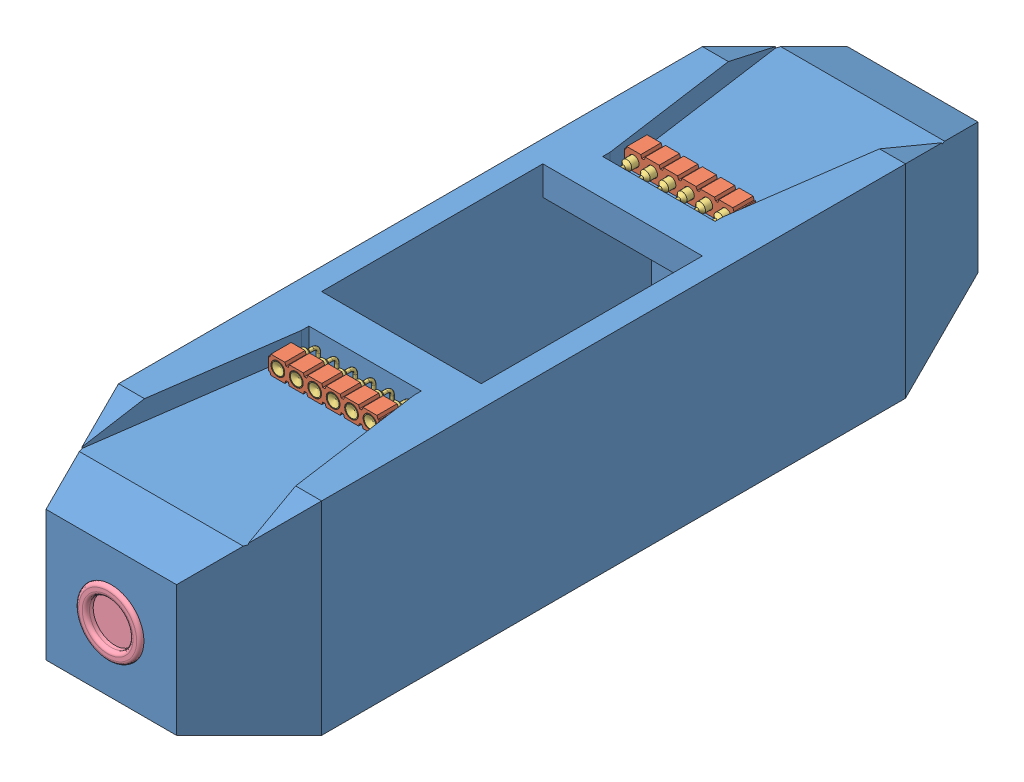
SolidWorks assembly Module_Laser, configuration Default. Lengths in mm.
Overall size (28 28 111.5).
19 component instances, 4 part files, 18 mates.
Components (placement in the parent):
- Module - RB_Gears-1: Module - RB_Gears [Laser] at (37.8746 66.7149 80.4494) size (28 28 110.5)
- mill-max-399-10-106-10-007000-1: mill-max-399-10-106-10-007000 [Default] at (87.4391 79.2849 107.5811) x (1 0 0) z (0 -1 0) size (15.24 5.81 5.74)
  - mill-max-399-10-106-10-007000_P3XX-11-010-00-000000(P306-11-010-00-000000)-1: mill-max-399-10-106-10-007000_P3XX-11-010-00-000000(P306-11-010-00-000000) [Default] at (-56.7488 -1.0694 1.27) size (15.24 2.79 2.54)
  - mill-max-399-10-106-10-007000_1960(1960-0-00-15-00-00-03-0)-1: mill-max-399-10-106-10-007000_1960(1960-0-00-15-00-00-03-0) [Default] at (-50.7044 -1.0694 0) x (0 -1 0) z (1 0 0) size (5.81 5.38 1.83)
  - mill-max-399-10-106-10-007000_1960(1960-0-00-15-00-00-03-0)-2: mill-max-399-10-106-10-007000_1960(1960-0-00-15-00-00-03-0) [Default] at (-43.0844 -1.0694 0) x (0 -1 0) z (1 0 0) size (5.81 5.38 1.83)
  - mill-max-399-10-106-10-007000_1960(1960-0-00-15-00-00-03-0)-3: mill-max-399-10-106-10-007000_1960(1960-0-00-15-00-00-03-0) [Default] at (-55.7844 -1.0694 0) x (0 -1 0) z (1 0 0) size (5.81 5.38 1.83)
  - mill-max-399-10-106-10-007000_1960(1960-0-00-15-00-00-03-0)-4: mill-max-399-10-106-10-007000_1960(1960-0-00-15-00-00-03-0) [Default] at (-48.1644 -1.0694 0) x (0 -1 0) z (1 0 0) size (5.81 5.38 1.83)
  - mill-max-399-10-106-10-007000_1960(1960-0-00-15-00-00-03-0)-5: mill-max-399-10-106-10-007000_1960(1960-0-00-15-00-00-03-0) [Default] at (-53.2444 -1.0694 0) x (0 -1 0) z (1 0 0) size (5.81 5.38 1.83)
  - mill-max-399-10-106-10-007000_1960(1960-0-00-15-00-00-03-0)-6: mill-max-399-10-106-10-007000_1960(1960-0-00-15-00-00-03-0) [Default] at (-45.6244 -1.0694 0) x (0 -1 0) z (1 0 0) size (5.81 5.38 1.83)
- mill-max-399-10-106-10-007000-2: mill-max-399-10-106-10-007000 [Default] at (-11.6898 79.2849 53.3178) x (-1 0 0) z (0 -1 0) size (15.24 5.81 5.74)
  - mill-max-399-10-106-10-007000_P3XX-11-010-00-000000(P306-11-010-00-000000)-1: mill-max-399-10-106-10-007000_P3XX-11-010-00-000000(P306-11-010-00-000000) [Default] at (-56.7488 -1.0694 1.27) size (15.24 2.79 2.54)
  - mill-max-399-10-106-10-007000_1960(1960-0-00-15-00-00-03-0)-1: mill-max-399-10-106-10-007000_1960(1960-0-00-15-00-00-03-0) [Default] at (-50.7044 -1.0694 0) x (0 -1 0) z (1 0 0) size (5.81 5.38 1.83)
  - mill-max-399-10-106-10-007000_1960(1960-0-00-15-00-00-03-0)-2: mill-max-399-10-106-10-007000_1960(1960-0-00-15-00-00-03-0) [Default] at (-43.0844 -1.0694 0) x (0 -1 0) z (1 0 0) size (5.81 5.38 1.83)
  - mill-max-399-10-106-10-007000_1960(1960-0-00-15-00-00-03-0)-3: mill-max-399-10-106-10-007000_1960(1960-0-00-15-00-00-03-0) [Default] at (-55.7844 -1.0694 0) x (0 -1 0) z (1 0 0) size (5.81 5.38 1.83)
  - mill-max-399-10-106-10-007000_1960(1960-0-00-15-00-00-03-0)-4: mill-max-399-10-106-10-007000_1960(1960-0-00-15-00-00-03-0) [Default] at (-48.1644 -1.0694 0) x (0 -1 0) z (1 0 0) size (5.81 5.38 1.83)
  - mill-max-399-10-106-10-007000_1960(1960-0-00-15-00-00-03-0)-5: mill-max-399-10-106-10-007000_1960(1960-0-00-15-00-00-03-0) [Default] at (-53.2444 -1.0694 0) x (0 -1 0) z (1 0 0) size (5.81 5.38 1.83)
  - mill-max-399-10-106-10-007000_1960(1960-0-00-15-00-00-03-0)-6: mill-max-399-10-106-10-007000_1960(1960-0-00-15-00-00-03-0) [Default] at (-45.6244 -1.0694 0) x (0 -1 0) z (1 0 0) size (5.81 5.38 1.83)
- 9mmx24mmLaser-1: 9mmx24mmLaser [Default] at (37.8746 66.7149 112.1994) x (0 0 1) z (-1 0 0) size (24 9 9)
- 9mmx24mmLaser-2: 9mmx24mmLaser [Default] at (37.8746 66.7149 48.6994) x (0 0 -1) z (0.449591 -0.893234 0) size (24 9 9)
Mates (geometry in assembly coordinates):
- Coincident1: coincident anti-aligned: plane of Module - RB_Gears-1 through (37.8746 66.7149 26.6994) normal (0 0 1); plane of ? through (43.8746 71.7149 26.6994) normal (0 0 -1)
- Coincident2: coincident anti-aligned: plane of Module - RB_Gears-1 through (37.8746 66.7149 134.1994) normal (0 0 -1); plane of ? through (31.8746 71.7149 134.1994) normal (0 0 1)
- Concentric1: concentric anti-aligned: cylinder of Module - RB_Gears-1 through (37.8746 66.7149 20.9568) axis (0 0 1) radius 1.5; cylinder of ? through (37.8746 66.7149 22.1994) axis (0 0 -1) radius 1.5
- Concentric2: concentric aligned: cylinder of Module - RB_Gears-1 through (42.3746 66.7149 20.9568) axis (0 0 1) radius 0.95; cylinder of ? through (42.3746 66.7149 27.0994) axis (0 0 1) radius 0.8
- Concentric3: concentric anti-aligned: cylinder of Module - RB_Gears-1 through (37.8746 66.7149 139.9421) axis (0 0 -1) radius 1.5; cylinder of ? through (37.8746 66.7149 138.6994) axis (0 0 1) radius 1.5
- Concentric4: concentric aligned: cylinder of Module - RB_Gears-1 through (42.3746 66.7149 139.9421) axis (0 0 -1) radius 0.95; cylinder of ? through (42.3746 66.7149 133.7994) axis (0 0 -1) radius 0.8
- Tangent1: tangent anti-aligned: plane of Module - RB_Gears-1 through (45.6246 78.0149 100.6994) normal (0 0 1); cylinder of mill-max-399-10-106-10-007000-1/mill-max-399-10-106-10-007000_1960(1960-0-00-15-00-00-03-0)-2 through (44.3546 84.5216 100.928) axis (0 1 0) radius 0.2286
- Tangent2: tangent anti-aligned: plane of Module - RB_Gears-1 through (45.6246 78.0149 100.6994) normal (0 0 1); cylinder of mill-max-399-10-106-10-007000-1/mill-max-399-10-106-10-007000_1960(1960-0-00-15-00-00-03-0)-3 through (31.6546 84.5216 100.928) axis (0 1 0) radius 0.2286
- Tangent3: tangent anti-aligned: plane of Module - RB_Gears-1 through (45.6246 78.0149 60.1994) normal (0 0 -1); cylinder of mill-max-399-10-106-10-007000-2/mill-max-399-10-106-10-007000_1960(1960-0-00-15-00-00-03-0)-2 through (31.3946 84.5216 59.9708) axis (0 1 0) radius 0.2286
- Tangent4: tangent anti-aligned: plane of Module - RB_Gears-1 through (45.6246 78.0149 60.1994) normal (0 0 -1); cylinder of mill-max-399-10-106-10-007000-2/mill-max-399-10-106-10-007000_1960(1960-0-00-15-00-00-03-0)-3 through (44.0946 84.5216 59.9708) axis (0 1 0) radius 0.2286
- Coincident3: coincident anti-aligned: plane of Module - RB_Gears-1 through (37.8746 78.0149 80.4494) normal (0 1 0); plane of mill-max-399-10-106-10-007000-2/mill-max-399-10-106-10-007000_P3XX-11-010-00-000000(P306-11-010-00-000000)-1 through (45.059 78.0149 57.1811) normal (0 -1 0)
- Coincident4: coincident anti-aligned: plane of Module - RB_Gears-1 through (37.8746 78.0149 80.4494) normal (0 1 0); plane of mill-max-399-10-106-10-007000-1/mill-max-399-10-106-10-007000_P3XX-11-010-00-000000(P306-11-010-00-000000)-1 through (30.6903 78.0149 103.7177) normal (0 -1 0)
- Coincident5: coincident anti-aligned: plane of Module - RB_Gears-1 through (45.6246 78.0149 120.6994) normal (-1 0 0); plane of mill-max-399-10-106-10-007000-1/mill-max-399-10-106-10-007000_P3XX-11-010-00-000000(P306-11-010-00-000000)-1 through (45.6246 80.1549 103.7177) normal (1 0 0)
- Coincident7: coincident anti-aligned: plane of Module - RB_Gears-1 through (30.1246 78.0149 40.1994) normal (1 0 0); plane of mill-max-399-10-106-10-007000-2/mill-max-399-10-106-10-007000_P3XX-11-010-00-000000(P306-11-010-00-000000)-1 through (30.1246 80.1549 57.1811) normal (-1 0 0)
- Concentric5: concentric anti-aligned: cylinder of Module - RB_Gears-1 through (37.8746 66.7149 93.1774) axis (0 0 -1) radius 4.5; cylinder of 9mmx24mmLaser-2 through (37.8746 66.7149 24.6994) axis (0 0 1) radius 4.5
- Concentric6: concentric anti-aligned: cylinder of Module - RB_Gears-1 through (37.8746 66.7149 67.7215) axis (0 0 1) radius 4.5; cylinder of 9mmx24mmLaser-1 through (37.8746 66.7149 136.1994) axis (0 0 -1) radius 4.5
- Coincident8: coincident anti-aligned: plane of Module - RB_Gears-1 through (37.8746 66.7149 135.6994) normal (0 0 1); circle of 9mmx24mmLaser-1
- Coincident9: coincident anti-aligned: plane of Module - RB_Gears-1 through (37.8746 66.7149 25.1994) normal (0 0 -1); circle of 9mmx24mmLaser-2
